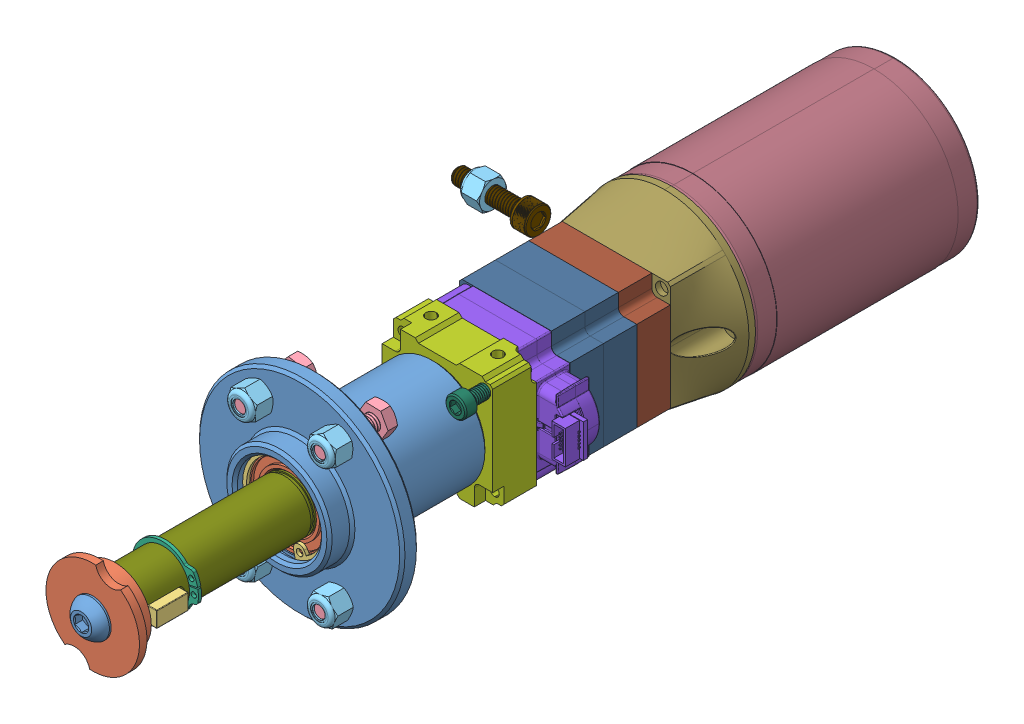
SolidWorks assembly PB2023-M054 DRIVETRAIN ASSEMBLY, configuration Default. Lengths in mm.
Overall size (85.83 78 344.65).
40 component instances, 21 part files, 16 mates.
Components (placement in the parent):
- A12220103_FRONT_BRACKET_ASSEMBLY-1: A12220103_FRONT_BRACKET_ASSEMBLY [Default] at origin size (78 78 534.65)
  - A12220101_FRONT_CASE_ASSEMBLY-1: A12220101_FRONT_CASE_ASSEMBLY [Default] at origin size (78 78 141.2)
    - 12220103_FRONT_HOUSING-1: 12220103_FRONT_HOUSING [Default] at (-52 141.0744 -192.9876) x (0 0 -1) z (1 0 0) size (60 78 78)
    - BALL BEARING-1: BALL BEARING [6656K203] at origin size (32 32 10)
    - BALL BEARING-2: BALL BEARING [6656K203] at (0 0 41) size (32 32 10)
    - Internal Retaining Ring (98455A129)-1: Internal Retaining Ring (98455A129) [98455A129] at (0.0361 0.7992 46) x (0.998982 -0.045107 0) z (0 0 1) size (34.4 33.81 1.2)
  - M6 x 20mm Steel Hex Head Screw (91310A333)-2: M6 x 20mm Steel Hex Head Screw (91310A333) [91310A333] at (-15.125 -26.1973 37.15) x (0 0 1) z (-0.44141 0.897306 0) size (24.4 11.55 10)
  - M6 x 1mm Steel Hex LockNut (90592A016)-1: M6 x 1mm Steel Hex LockNut (90592A016) [97260A101] at (15.125 -26.1973 41.85) x (0.928554 -0.371196 0) z (-0.371196 -0.928554 0) size (10 8.38 11.55)
  - 20MM External Retaining Ring (98541A123)-4: 20MM External Retaining Ring (98541A123) [98541A123] at (0 0 92.94) x (0 0 1) z (-0.186581 0.98244 0) size (1.2 25.1 22.76)
  - A12220110_FRONT_SHAFT_ASSEMBLY-1: A12220110_FRONT_SHAFT_ASSEMBLY [Default] at (1.7896 0 -19.01) x (0 -1 0) z (0 0 1) size (64.01 67.32 307.03)
    - A12220105_MOTOR_BRACKET_ASSEMBLY-1: A12220105_MOTOR_BRACKET_ASSEMBLY [Default] at origin size (64.01 67.32 280.24) (flexible)
      - 12220106-051 MiniCIM Motor Assembly-1: 12220106-051 MiniCIM Motor Assembly [Default] at origin size (64.01 67.32 218.97)
        - Gearbox Assembly-1: Gearbox Assembly [Default] at (34.0244 -12.4567 -92.7758) x (0 0 1) z (-1 0 0) size (123.35 56.32 44.45)
          - Output Housing-2: Output Housing [Default] at (64.8023 -0.856 18.2213) x (1 0 0) z (0 -1 0) size (75.7 44.45 56.32)
            - Housing-1: Housing [Default] at (19.8785 -6.4219 -11.5232) size (18.13 44.45 42)
            - Encoder.step-1: Encoder.step [Default] at (12.6785 15.8031 -11.5232) x (0 0 1) z (-1 0 0) size (56.32 42 21.21)
            - Gearbox_output_shaft-1: Gearbox_output_shaft [Default] at origin size (63.51 17 17)
          - Ring Gears-1: Ring Gears [Default] at (71.9808 10.6671 11.7994) x (1 0 0) z (0 -1 0) size (32.2 42 42)
          - Ring Gear Stage 3-1: Ring Gear Stage 3 [Default] at (59.2808 10.6671 11.7994) x (1 0 0) z (0 -1 0) size (28.65 42 42)
        - CIM Adaptor.step-1: CIM Adaptor.step [Default] at (0 -1.7896 -68.72) x (0 -1 0) z (-1 0 0) size (64.01 21.63 64.01)
        - Mini CIM-1: Mini CIM [Default] at (0 -1.7896 -80.245) x (0 0 -1) z (1 0 0) size (101.22 64.01 64.01)
        - 8-32 X 3IN LG - Black-Oxide Alloy Steel Socket Head Screw (90044A516)-1: 8-32 X 3IN LG - Black-Oxide Alloy Steel Socket Head Screw (90044A516) [90044A516] at (17.5 15.7104 -75.245) x (-0.08536 0.99635 0) z (0 0 -1) size (6.86 6.86 81.33)
        - 8-32 X 3IN LG - Black-Oxide Alloy Steel Socket Head Screw (90044A516)-3: 8-32 X 3IN LG - Black-Oxide Alloy Steel Socket Head Screw (90044A516) [90044A516] at (-17.5 -19.2896 -75.245) x (-0.242255 0.970213 0) z (0 0 -1) size (6.86 6.86 81.33)
      - 10-32 X 0.875IN LG - Black-Oxide Alloy Steel Socket Head Screw (91251A346)-1: 10-32 X 0.875IN LG - Black-Oxide Alloy Steel Socket Head Screw (91251A346) [91251A346] at (-17.9605 16.1709 6.1805) x (0.130335 0.99147 0) z (0 0 1) size (7.94 7.94 27.67)
      - 10-32 X 0.875IN LG - Black-Oxide Alloy Steel Socket Head Screw (91251A346)-2: 10-32 X 0.875IN LG - Black-Oxide Alloy Steel Socket Head Screw (91251A346) [91251A346] at (17.9605 -19.7501 6.1805) x (0.872398 0.488796 0) z (0 0 1) size (7.94 7.94 27.67)
    - PB2023-M005 ROTARY SHAFT-1: PB2023-M005 ROTARY SHAFT [Default] at (0 -1.7896 136.57) x (0 0 -1) z (1 0 0) size (126.56 25 25)
    - 12220110_MOTOR_KEY-1: 12220110_MOTOR_KEY [Default] at (0 5.1764 16.3975) size (3.17 4.76 26.16)
  - M6 x 20mm Steel Hex Head Screw (91310A333)-7: M6 x 20mm Steel Hex Head Screw (91310A333) [91310A333] at (15.125 -26.1973 37.15) x (0 0 1) z (0.78025 0.625468 0) size (24.4 11.55 10)
  - M6 x 20mm Steel Hex Head Screw (91310A333)-9: M6 x 20mm Steel Hex Head Screw (91310A333) [91310A333] at (15.125 26.1973 37.15) x (0 0 1) z (0.877007 0.480477 0) size (24.4 11.55 10)
  - M6 x 20mm Steel Hex Head Screw (91310A333)-11: M6 x 20mm Steel Hex Head Screw (91310A333) [91310A333] at (-15.0958 26.1466 37.15) x (0 0 1) z (0.947118 0.320887 0) size (24.4 11.55 10)
  - M6 x 1mm Steel Hex LockNut (90592A016)-7: M6 x 1mm Steel Hex LockNut (90592A016) [97260A101] at (-15.125 -26.1973 41.85) x (0.975663 -0.219276 0) z (-0.219276 -0.975663 0) size (10 8.38 11.55)
  - M6 x 1mm Steel Hex LockNut (90592A016)-9: M6 x 1mm Steel Hex LockNut (90592A016) [97260A101] at (-15.125 26.1973 41.85) x (0.995642 -0.093258 0) z (-0.093258 -0.995642 0) size (10 8.38 11.55)
  - M6 x 1mm Steel Hex LockNut (90592A016)-11: M6 x 1mm Steel Hex LockNut (90592A016) [97260A101] at (15.2049 26.151 41.85) x (1 -0.000046 0) z (-0.000046 -1 0) size (10 8.38 11.55)
- M6 x 25mm Steel Socket Head Screw (91290A330)-1: M6 x 25mm Steel Socket Head Screw (91290A330) [91290A330] at (-31.155 30 -64.48) x (0 -0.901175 -0.433456) z (1 0 0) size (10 10 31.46)
- M6 x 25mm Steel Socket Head Screw (91290A330)-2: M6 x 25mm Steel Socket Head Screw (91290A330) [91290A330] at (-31.155 -30 -64.48) x (0 -0.15786 -0.987461) z (1 0 0) size (10 10 31.46)
- M6 x 1mm Steel Hex LockNut (90592A016)-1: M6 x 1mm Steel Hex LockNut (90592A016) [97260A101] at (-33 -30 -64.48) x (0 0.608626 0.793457) z (0 -0.793457 0.608626) size (10 8.38 11.55)
- M6 x 1mm Steel Hex LockNut (90592A016)-2: M6 x 1mm Steel Hex LockNut (90592A016) [97260A101] at (-33 30 -64.48) x (0 -0.994883 0.101031) z (0 -0.101031 -0.994883) size (10 8.38 11.55)
- M8 X 20MM - 18-8 Stainless Steel Button Head Hex Drive Screws (97763A444)-1: M8 X 20MM - 18-8 Stainless Steel Button Head Hex Drive Screws (97763A444) [97763A444] at (0 0 124.825) x (0.999813 0.019347 0) z (0 0 1) size (14 14 25.15)
- PB2023-M006 WHEEL END CAP CUSTOM WASHER-1: PB2023-M006 WHEEL END CAP CUSTOM WASHER [Default] at (0 0 117.56) x (0 0 -1) z (-0.345262 -0.938506 0) size (8.5 35.5 34.05)
- 98870A743_Machine Key-1: 98870A743_Machine Key [98870A743] at (10 0 103.06) size (6 6 12)
Mates (geometry in assembly coordinates):
- Coincident4: coordinate: point of A12220103_FRONT_BRACKET_ASSEMBLY-1
- Concentric5: concentric aligned: cylinder of A12220103_FRONT_BRACKET_ASSEMBLY-1/12220105_SUPPORT_BRACKET-1 through (-16.8 -30 -64.48) axis (-1 0 0) radius 3.5; cylinder of M6 x 1mm Steel Hex LockNut (90592A016)-1 through (-39.85 -30 -64.48) axis (-1 0 0) radius 2.375
- Coincident7: coincident anti-aligned: plane of A12220103_FRONT_BRACKET_ASSEMBLY-1/12220105_SUPPORT_BRACKET-1 through (-33 0 35.5) normal (-1 0 0); plane of M6 x 1mm Steel Hex LockNut (90592A016)-1 through (-33 -26.1716 -73.7181) normal (1 0 0)
- Concentric6: concentric aligned: cylinder of A12220103_FRONT_BRACKET_ASSEMBLY-1/12220105_SUPPORT_BRACKET-1 through (-16.8 30 -64.48) axis (-1 0 0) radius 3.5; cylinder of M6 x 1mm Steel Hex LockNut (90592A016)-2 through (-39.85 30 -64.48) axis (-1 0 0) radius 2.375
- Coincident8: coincident anti-aligned: plane of A12220103_FRONT_BRACKET_ASSEMBLY-1/12220105_SUPPORT_BRACKET-1 through (-33 0 35.5) normal (-1 0 0); plane of M6 x 1mm Steel Hex LockNut (90592A016)-2 through (-33 35.8494 -56.3692) normal (1 0 0)
- Concentric14: concentric aligned: cylinder of A12220103_FRONT_BRACKET_ASSEMBLY-1/A12220110_FRONT_SHAFT_ASSEMBLY-1/A12220105_MOTOR_BRACKET_ASSEMBLY-1/12220106_MOTOR_BRACKET-1 through (-21.655 -30 -64.48) axis (-1 0 0) radius 3.5; cylinder of M6 x 25mm Steel Socket Head Screw (91290A330)-2 through (-46.655 -30 -64.48) axis (-1 0 0) radius 5
- Coincident20: coincident anti-aligned: plane of A12220103_FRONT_BRACKET_ASSEMBLY-1/A12220110_FRONT_SHAFT_ASSEMBLY-1/A12220105_MOTOR_BRACKET_ASSEMBLY-1/12220106_MOTOR_BRACKET-1 through (-21.655 0 -10.48) normal (1 0 0); plane of M6 x 25mm Steel Socket Head Screw (91290A330)-2 through (-21.655 -29.2581 -59.8389) normal (-1 0 0)
- Concentric15: concentric aligned: cylinder of A12220103_FRONT_BRACKET_ASSEMBLY-1/A12220110_FRONT_SHAFT_ASSEMBLY-1/A12220105_MOTOR_BRACKET_ASSEMBLY-1/12220106_MOTOR_BRACKET-1 through (-21.655 30 -64.48) axis (-1 0 0) radius 3.5; cylinder of M6 x 25mm Steel Socket Head Screw (91290A330)-1 through (-46.655 30 -64.48) axis (-1 0 0) radius 5
- Coincident21: coincident anti-aligned: plane of A12220103_FRONT_BRACKET_ASSEMBLY-1/A12220110_FRONT_SHAFT_ASSEMBLY-1/A12220105_MOTOR_BRACKET_ASSEMBLY-1/12220106_MOTOR_BRACKET-1 through (-21.655 0 -10.48) normal (1 0 0); plane of M6 x 25mm Steel Socket Head Screw (91290A330)-1 through (-21.655 34.2355 -62.4428) normal (-1 0 0)
- Concentric17: concentric aligned: cylinder of M8 X 20MM - 18-8 Stainless Steel Button Head Hex Drive Screws (97763A444)-1 through (0 0 124.825) axis (0 0 1) radius 7; cylinder of 12220117_CUSTOM_WASHER-1 through (0 0 120.425) axis (0 0 1) radius 5
- Coincident22: coincident anti-aligned: plane of M8 X 20MM - 18-8 Stainless Steel Button Head Hex Drive Screws (97763A444)-1 through (0.1354 -6.9987 120.425) normal (0 0 -1); plane of 12220117_CUSTOM_WASHER-1 through (3.9887 -1.4674 120.425) normal (0 0 1)
- Concentric18: concentric aligned: circle of A12220103_FRONT_BRACKET_ASSEMBLY-1/A12220110_FRONT_SHAFT_ASSEMBLY-1/12220102_FRONT_SHAFT-1; circle of 12220117_CUSTOM_WASHER-1
- Coincident23: coincident anti-aligned: plane of A12220103_FRONT_BRACKET_ASSEMBLY-1/A12220110_FRONT_SHAFT_ASSEMBLY-1/12220102_SHAFT-1 through (0 0 117.56) normal (0 0 1); plane of 12220117_CUSTOM_WASHER-1 through (3.9887 -1.4674 117.56) normal (0 0 -1)
- Coincident24: coincident anti-aligned: plane of A12220103_FRONT_BRACKET_ASSEMBLY-1/A12220110_FRONT_SHAFT_ASSEMBLY-1/12220102_SHAFT-1 through (0 -3 95.56) normal (0 1 0); plane of 98870A743_Machine Key-1 through (13 -3 109.06) normal (0 -1 0)
- Coincident25: coincident anti-aligned: plane of A12220103_FRONT_BRACKET_ASSEMBLY-1/A12220110_FRONT_SHAFT_ASSEMBLY-1/12220102_SHAFT-1 through (7 0 95.56) normal (1 0 0); plane of 98870A743_Machine Key-1 through (7 -3 109.06) normal (-1 0 0)
- Distance1: distance = 1.5 mm anti-aligned: plane of 98870A743_Machine Key-1 through (10 0 97.06) normal (0 0 -1); plane of A12220103_FRONT_BRACKET_ASSEMBLY-1/A12220110_FRONT_SHAFT_ASSEMBLY-1/12220102_SHAFT-1 through (0 0 95.56) normal (0 0 1)
